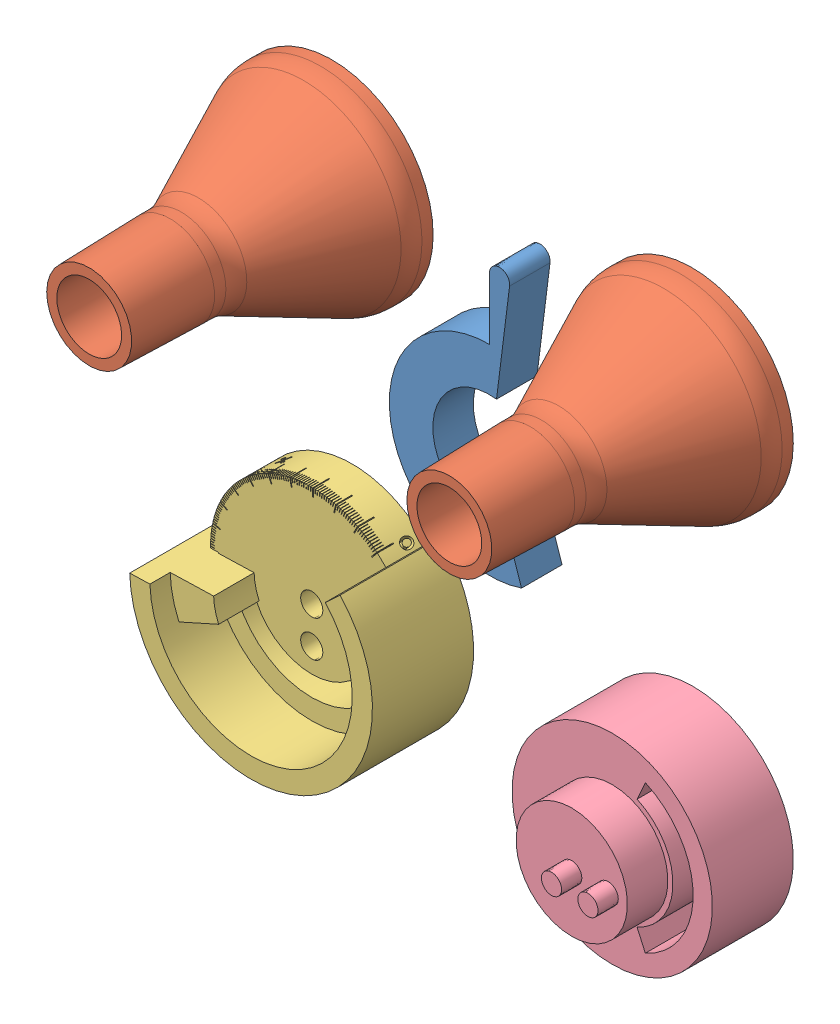
SolidWorks assembly Montagem_impressão, configuration Valor predeterminado. Lengths in mm.
Overall size (154.34 147.17 60.16).
5 component instances, 4 part files, 15 mates.
Components (placement in the parent):
- Catraca-1: Catraca [Valor predeterminado] at (4.4207 13.2837 0) x (0.992278 -0.124035 0) z (0 0 1) size (35.53 67.25 10)
- Peça 1 - Funil-1: Peça 1 - Funil [Valor predeterminado] at (-44.5 44.5 5) x (-0.923728 -0.383049 0) z (0 0 -1) size (50 50 60.16)
- Peça 1 - Funil-2: Peça 1 - Funil [Valor predeterminado] at (44.5 44.5 5) x (-0.923728 -0.383049 0) z (0 0 -1) size (50 50 60.16)
- Peça 2-1: Peça 2 [Valor predeterminado] at (-39.5 -39.5 0) x (1 0 0) z (0 -1 0) size (59.99 25 55)
- Peça 3-1: Peça 3 [Valor predeterminado] at (44.75 -44.75 0) x (1 0 0) z (0 -1 0) size (49.5 35 49.5)
Mates (geometry in assembly coordinates):
- Coincident3: coincident: plane of assembly through (0 0 0) normal (0 0 1); plane of Peça 2-1 through (-39.5 -39.5 0) normal (0 0 -1); plane of assembly
- Coincident4: coincident: plane of assembly through (0 0 0) normal (0 0 1); plane of Peça 3-1 through (44.75 -44.75 0) normal (0 0 -1); plane of assembly
- Coincident6: coincident: plane of assembly through (4.7936 40.0262 102.5781) normal (0 0 1); plane of Peça 1 - Funil-1 through (-44.5 44.5 0) normal (0 0 -1); plane of assembly
- Coincident7: coincident: plane of assembly through (0 0 0) normal (0 0 1); plane of Peça 1 - Funil-2 through (44.5 44.5 0) normal (0 0 -1); plane of assembly
- Coincident8: coincident: plane of assembly through (0 0 0) normal (0 0 1); plane of Catraca-1 through (4.4207 13.2837 0) normal (0 0 -1); plane of assembly
- Tangent1: tangent: cylinder of assembly; cylinder of Peça 2-1 through (-39.5 -39.5 -78.3497) axis (0 0 1) radius 30; line of assembly
- Tangent2: tangent: cylinder of assembly; cylinder of Peça 2-1 through (-39.5 -39.5 -78.3497) axis (0 0 1) radius 30; line of assembly
- Tangent3: tangent: cylinder of assembly; cylinder of Peça 3-1 through (44.75 -44.75 20) axis (0 0 -1) radius 24.75; line of assembly
- Tangent4: tangent: cylinder of assembly; cylinder of Peça 3-1 through (44.75 -44.75 20) axis (0 0 -1) radius 24.75; line of assembly
- Tangent5: tangent: cylinder of assembly; cylinder of Peça 1 - Funil-2 through (44.5 44.5 0) axis (0 0 1) radius 25; line of assembly
- Tangent6: tangent: cylinder of assembly; cylinder of Peça 1 - Funil-2 through (44.5 44.5 0) axis (0 0 1) radius 25; line of assembly
- Tangent7: tangent: cylinder of assembly; cylinder of Peça 1 - Funil-1 through (-44.5 44.5 0) axis (0 0 1) radius 25; line of assembly
- Tangent8: tangent: cylinder of assembly; cylinder of Peça 1 - Funil-1 through (-44.5 44.5 0) axis (0 0 1) radius 25; line of assembly
- Coincident13: coincident: circle of assembly; circle of Catraca-1; point of assembly
- Parallel5: parallel: line of assembly; line of Catraca-1 through (15.5613 4.4207 53.595) axis (0 0 -1); line of assembly
